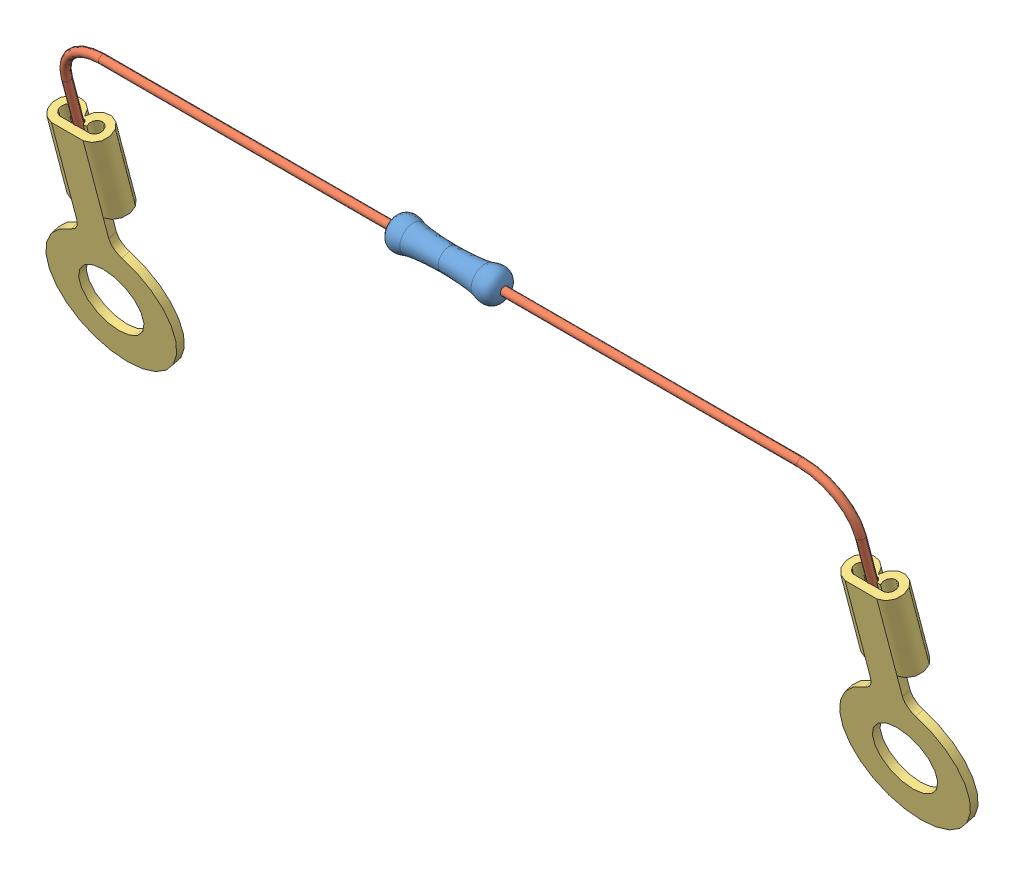
SolidWorks assembly Resistance, configuration Défaut. Lengths in mm.
Overall size (58 21.38 7.45).
4 component instances, 3 part files, 5 mates.
Components (placement in the parent):
- Resistance-1: Resistance [Défaut] at (-32.6301 22.3345 0) size (7 2.17 2.17)
- ResistanceFil-1: ResistanceFil [Défaut] at (-57.462 11.6945 -2.7912) x (1 0 0) z (0 -0.253741 0.967272) size (50.5 11.25 0.5)
- CosseM4-1: CosseM4 [Défaut] at (-57.462 5.9106 -3.5559) x (1 0 0) z (0 0.967272 0.253741) size (8 1.85 14.94)
- CosseM4-2: CosseM4 [Défaut] at (-7.462 5.9106 -3.5559) x (1 0 0) z (0 0.967272 0.253741) size (8 1.85 14.94)
Mates (geometry in assembly coordinates):
- Coaxiale1: concentric anti-aligned: circle of Resistance-1; cylinder of ResistanceFil-1 through (-54.462 22.3345 0) axis (1 0 0) radius 0.25
- Coaxiale5: concentric anti-aligned: cylinder of ResistanceFil-1 through (-57.462 19.4327 -0.7612) axis (0 -0.967272 -0.253741) radius 0.25; circle of CosseM4-1
- Coaxiale6: concentric anti-aligned: cylinder of ResistanceFil-1 through (-7.462 19.4327 -0.7612) axis (0 -0.967272 -0.253741) radius 0.25; circle of CosseM4-2
- Coïncidente1: coincident aligned: plane of CosseM4-1 through (-59.462 10.3432 -2.3931) normal (0 -0.253741 0.967272); plane of CosseM4-2 through (-9.462 10.3432 -2.3931) normal (0 -0.253741 0.967272)
- Coïncidente4: coincident aligned: plane of CosseM4-1 through (-58.462 16.6183 -1.2639) normal (0 0.967272 0.253741); plane of CosseM4-2 through (-8.462 16.6183 -1.2639) normal (0 0.967272 0.253741)
